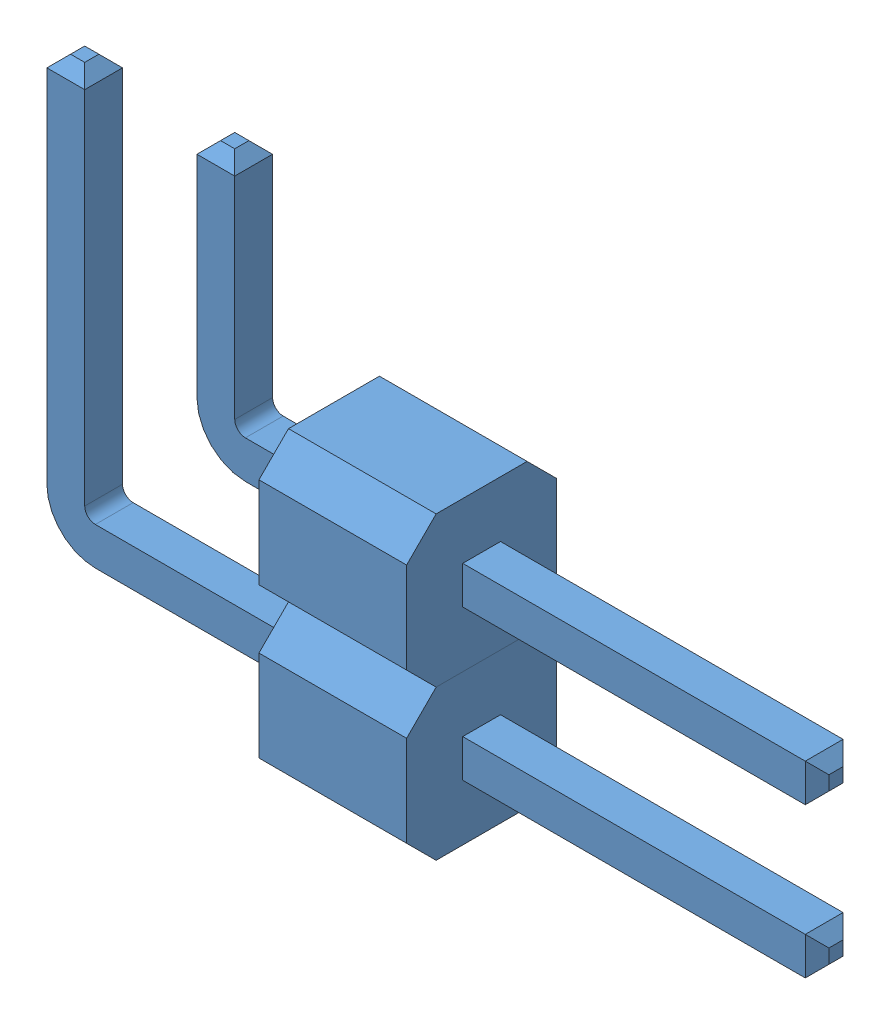
SolidWorks assembly pls_2x1_90_v3, configuration По умолчанию. Lengths in mm.
Overall size (13.04 10.62 2.54).
2 component instances, 1 part files, 3 mates.
Components (placement in the parent):
- pld90_1_v3-1: pld90_1_v3 [Top] at (5.8512 -3.1222 1.2116) size (13.04 8.08 2.54)
- pld90_1_v3-2: pld90_1_v3 [По умолчанию] at (5.8512 -0.5822 1.2116) size (13.04 8.08 2.54)
Mates (geometry in assembly coordinates):
- Совпадение1: coincident anti-aligned: plane of pld90_1_v3-1 through (-2.6488 -1.8522 2.4816) normal (0 1 0); plane of pld90_1_v3-2 through (-2.6488 -1.8522 2.4816) normal (0 -1 0)
- Совпадение2: coincident aligned: plane of pld90_1_v3-1 through (-0.1488 -3.1222 1.2116) normal (1 0 0); plane of pld90_1_v3-2 through (-0.1488 -0.5822 1.2116) normal (1 0 0)
- Совпадение3: coincident aligned: plane of pld90_1_v3-1 through (-2.6488 -1.8522 2.4816) normal (0 0 1); plane of pld90_1_v3-2 through (-2.6488 0.6878 2.4816) normal (0 0 1)
